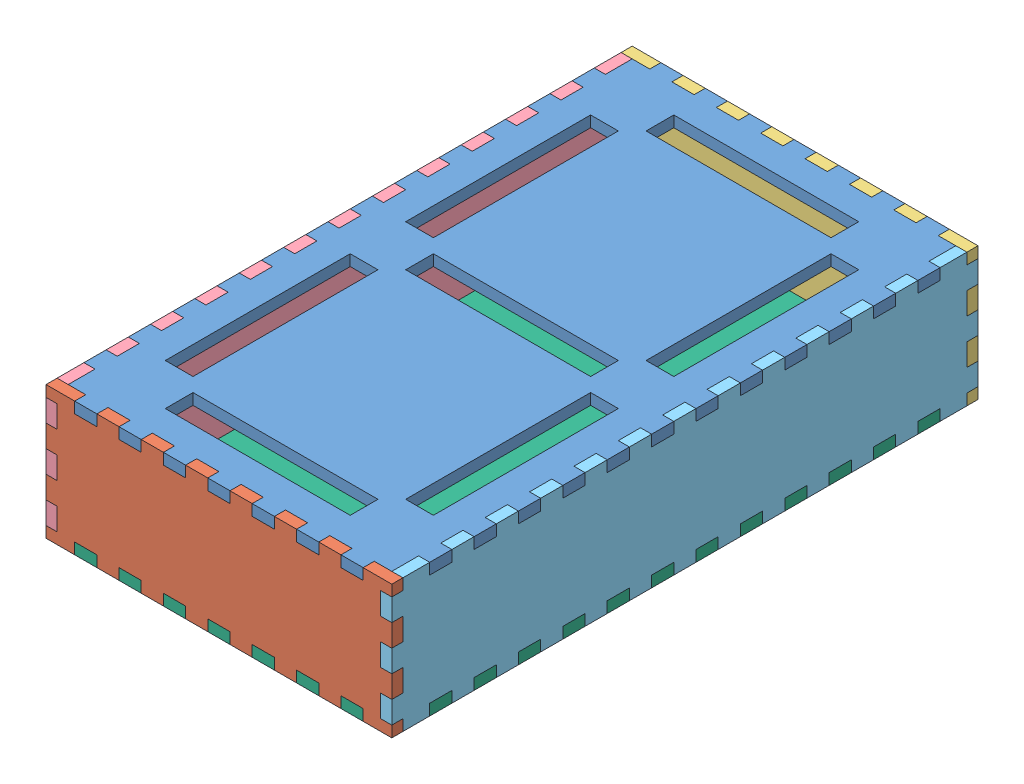
SolidWorks assembly assembly, configuration Default. Lengths in mm.
Overall size (187 72 317).
6 component instances, 6 part files, 20 mates.
Components (placement in the parent):
- TOP_PLANE-1: TOP_PLANE [Default] at (119.8504 168.3829 240.5135) size (187 6 317)
- FRONT_PLANE-1: FRONT_PLANE [Default] at (119.8504 168.3829 393.0135) size (187 72 6)
- BACK_PLANE-1: BACK_PLANE [Default] at (119.8504 168.3829 88.0135) x (-1 0 0) z (0 0 -1) size (187 72 6)
- LEFT_SIDE_PLANE-1: LEFT_SIDE_PLANE [Default] at (26.3504 168.3829 240.5135) x (0 0 1) z (-1 0 0) size (317 72 6)
- RIGHT_SIDE_PLANE-1: RIGHT_SIDE_PLANE [Default] at (207.3504 168.3829 240.5135) x (0 0 -1) z (1 0 0) size (317 72 6)
- BOTTOM_PLANE-1: BOTTOM_PLANE [Default] at (119.8504 108.3829 393.0135) x (-1 0 0) z (0 -1 0) size (187 317 6)
Mates (geometry in assembly coordinates):
- InPlace1: in place: plane of TOP_PLANE-1 through (32.3504 178.3829 393.0135) normal (0 0 1); plane of ? through (0 0 393.0135) normal (0 0 1); moOrthogonalPlaneRef_w of TOP_PLANE-1 through (32.3504 178.3829 393.0135) normal (0 0 1); plane of ? through (0 0 393.0135) normal (0 1 0); plane of TOP_PLANE-1 through (32.3504 178.3829 393.0135) normal (0 0 1); plane of ? through (0 0 393.0135) normal (1 0 0); plane of TOP_PLANE-1 through (32.3504 174.3829 393.0135) normal (0 0 1); unknown of FRONT_PLANE-1
- Coincident1: coincident aligned: plane of ?; plane of ?
- Coincident2: coincident aligned: moOrthogonalPlaneRef_w of Bovenzijde-1 through (119.8504 168.3829 393.0135) normal (0 1 0); plane of front plane-1 through (119.8504 168.3829 393.0135) normal (0 1 0)
- Coincident3: coincident anti-aligned: moOrthogonalPlaneRef_w of Bovenzijde-1 through (119.8504 168.3829 393.0135) normal (-1 0 0); plane of front plane-1 through (119.8504 168.3829 393.0135) normal (1 0 0)
- InPlace2: in place: plane of TOP_PLANE-1 through (32.3504 174.3829 88.0135) normal (0 0 -1); plane of ? through (0 0 88.0135) normal (0 0 -1); plane of TOP_PLANE-1 through (32.3504 174.3829 88.0135) normal (0 0 -1); plane of ? through (0 0 88.0135) normal (0 1 0); plane of TOP_PLANE-1 through (32.3504 174.3829 88.0135) normal (0 0 -1); plane of ? through (0 0 88.0135) normal (-1 0 0); plane of TOP_PLANE-1 through (32.3504 174.3829 88.0135) normal (0 0 -1); unknown of BACK_PLANE-1
- Coincident4: coincident aligned: plane of ?; plane of ?
- Coincident5: coincident aligned: moOrthogonalPlaneRef_w of Bovenzijde-1 through (119.8504 168.3829 88.0135) normal (0 1 0); plane of back plane^assembly-1 through (119.8504 168.3829 88.0135) normal (0 1 0)
- Coincident6: coincident anti-aligned: moOrthogonalPlaneRef_w of Bovenzijde-1 through (119.8504 168.3829 88.0135) normal (1 0 0); plane of back plane^assembly-1 through (119.8504 168.3829 88.0135) normal (-1 0 0)
- InPlace3: in place: plane of TOP_PLANE-1 through (26.3504 174.3829 240.5135) normal (-1 0 0); plane of ? through (26.3504 0 0) normal (-1 0 0); plane of TOP_PLANE-1 through (26.3504 174.3829 240.5135) normal (-1 0 0); plane of ? through (26.3504 0 0) normal (0 1 0); plane of TOP_PLANE-1 through (26.3504 174.3829 240.5135) normal (-1 0 0); plane of ? through (26.3504 0 0) normal (0 0 1); plane of TOP_PLANE-1 through (26.3504 174.3829 240.5135) normal (-1 0 0); unknown of LEFT_SIDE_PLANE-1
- Coincident7: coincident aligned: plane of ?; plane of ?
- Coincident8: coincident aligned: moOrthogonalPlaneRef_w of Bovenzijde-1 through (26.3504 168.3829 240.5135) normal (0 1 0); plane of Part4^assembly-1 through (26.3504 168.3829 240.5135) normal (0 1 0)
- Coincident9: coincident anti-aligned: moOrthogonalPlaneRef_w of Bovenzijde-1 through (26.3504 168.3829 240.5135) normal (0 0 -1); plane of Part4^assembly-1 through (26.3504 168.3829 240.5135) normal (0 0 1)
- InPlace4: in place: plane of TOP_PLANE-1 through (207.3504 174.3829 393.0135) normal (1 0 0); plane of ? through (207.3504 0 0) normal (1 0 0); plane of TOP_PLANE-1 through (207.3504 174.3829 393.0135) normal (1 0 0); plane of ? through (207.3504 0 0) normal (0 1 0); plane of TOP_PLANE-1 through (207.3504 174.3829 393.0135) normal (1 0 0); plane of ? through (207.3504 0 0) normal (0 0 -1); plane of TOP_PLANE-1 through (207.3504 174.3829 393.0135) normal (1 0 0); unknown of RIGHT_SIDE_PLANE-1
- Coincident1: coincident aligned: plane of ?; plane of ?
- Coincident2: coincident aligned: moOrthogonalPlaneRef_w of Bovenzijde-1 through (207.3504 168.3829 240.5135) normal (0 1 0); plane of Part5^assembly-1 through (207.3504 168.3829 240.5135) normal (0 1 0)
- Coincident3: coincident anti-aligned: moOrthogonalPlaneRef_w of Bovenzijde-1 through (207.3504 168.3829 240.5135) normal (0 0 1); plane of Part5^assembly-1 through (207.3504 168.3829 240.5135) normal (0 0 -1)
- InPlace5: in place: plane of FRONT_PLANE-1 through (41.8504 108.3829 393.0135) normal (0 -1 0); plane of ? through (0 108.3829 0) normal (0 -1 0); plane of FRONT_PLANE-1 through (41.8504 108.3829 393.0135) normal (0 -1 0); plane of ? through (0 108.3829 0) normal (0 0 -1); plane of FRONT_PLANE-1 through (41.8504 108.3829 393.0135) normal (0 -1 0); plane of ? through (0 108.3829 0) normal (-1 0 0); plane of FRONT_PLANE-1 through (41.8504 108.3829 393.0135) normal (0 -1 0); unknown of BOTTOM_PLANE-1
- Coincident4: coincident aligned: plane of ?; plane of ?
- Coincident5: coincident aligned: moOrthogonalPlaneRef_w of front plane-1 through (119.8504 108.3829 393.0135) normal (0 0 -1); plane of Part8^assembly-1 through (119.8504 108.3829 393.0135) normal (0 0 -1)
- Coincident6: coincident anti-aligned: moOrthogonalPlaneRef_w of front plane-1 through (119.8504 108.3829 393.0135) normal (1 0 0); plane of Part8^assembly-1 through (119.8504 108.3829 393.0135) normal (-1 0 0)
